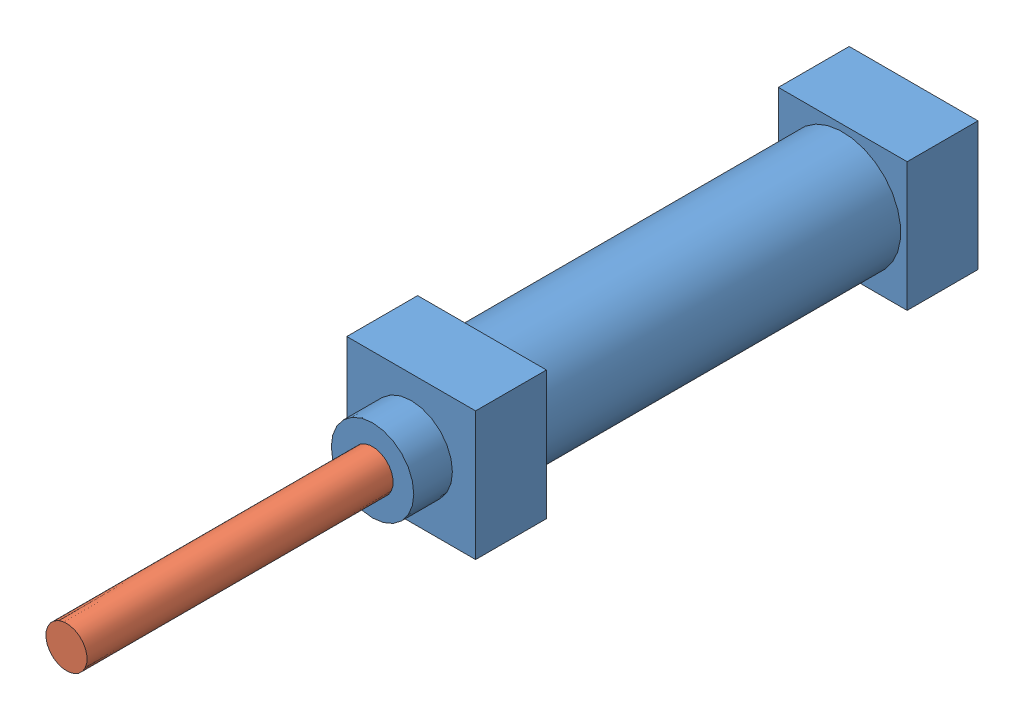
SolidWorks assembly Piston_assembly_v1, configuration Default. Lengths in mm.
Overall size (50 50 328.79).
2 component instances, 2 part files, 2 mates.
Components (placement in the parent):
- Cylinder-1: Cylinder [Default] at (97.7392 132.2426 -64.8029) size (50 50 210)
- Rod-1: Rod [Default] at (122.7392 157.2426 263.9903) x (-0.916372 0.400328 0) z (-0.400328 -0.916372 0) size (16 134 16)
Mates (geometry in assembly coordinates):
- Concentric1: concentric anti-aligned: cylinder of Cylinder-1 through (122.7392 157.2426 102.6971) axis (0 0 -1) radius 22.5; cylinder of Rod-1 through (122.7392 157.2426 45.1971) axis (0 0 1) radius 8
- LimitDistance2: limit distance = 34 mm aligned: plane of Rod-1 through (122.7392 157.2426 179.1971) normal (0 0 1); plane of Cylinder-1 through (122.7392 157.2426 145.1971) normal (0 0 1)
